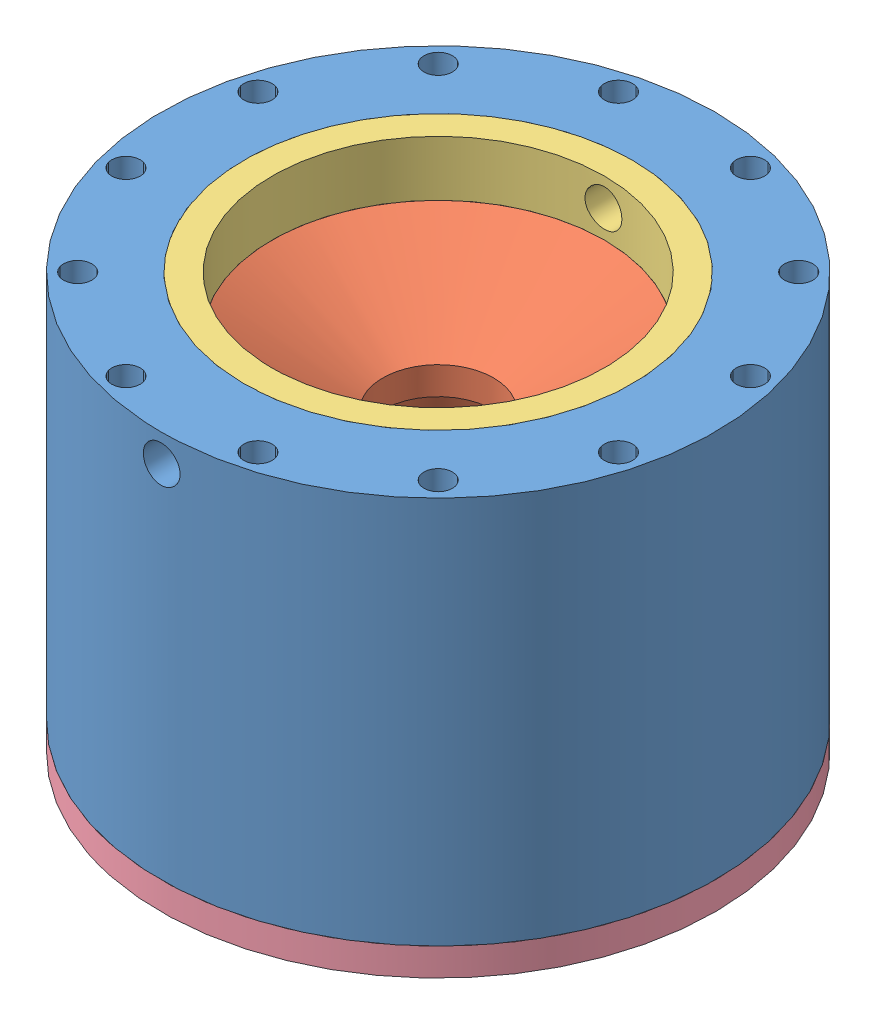
SolidWorks assembly Nozzle Extension, configuration Default. Lengths in mm.
Overall size (155.54 95.25 155.54).
4 component instances, 4 part files, 6 mates.
Components (placement in the parent):
- Combustion Chamber Nozzle Ext-1: Combustion Chamber Nozzle Ext [CHAMBER WITH SENSOR FEATURES] at origin size (127 88.9 127)
- New Nozzle-1: New Nozzle [Default] x (-1 0 0) z (0 0 -1) size (88.9 76.2 88.9)
- Graphite Ring-1: Graphite Ring [Default] at (0 76.2 0) size (88.9 12.7 88.9)
- Steel Retaining Ring-1: Steel Retaining Ring [Default] at (0 -6.35 0) x (0.965926 0 0.258819) z (-0.258819 0 0.965926) size (127 6.35 127)
Mates (geometry in assembly coordinates):
- Concentric1: concentric anti-aligned: circle of Combustion Chamber Nozzle Ext-1; circle of New Nozzle-1
- Coincident2: coincident aligned: plane of Combustion Chamber Nozzle Ext-1 through (0 0 0) normal (0 -1 0); plane of New Nozzle-1 through (28.321 0 0) normal (0 -1 0)
- Coincident3: coincident anti-aligned: circle of New Nozzle-1; circle of Graphite Ring-1
- Concentric2: concentric aligned: cylinder of Combustion Chamber Nozzle Ext-1 through (0 268.5051 0) axis (0 -1 0) radius 63.5; cylinder of Graphite Ring-1 through (0 88.9 0) axis (0 -1 0) radius 38.1
- Coincident4: coincident anti-aligned: circle of Combustion Chamber Nozzle Ext-1; circle of Steel Retaining Ring-1
- Concentric3: concentric anti-aligned: circle of Combustion Chamber Nozzle Ext-1; circle of Steel Retaining Ring-1
